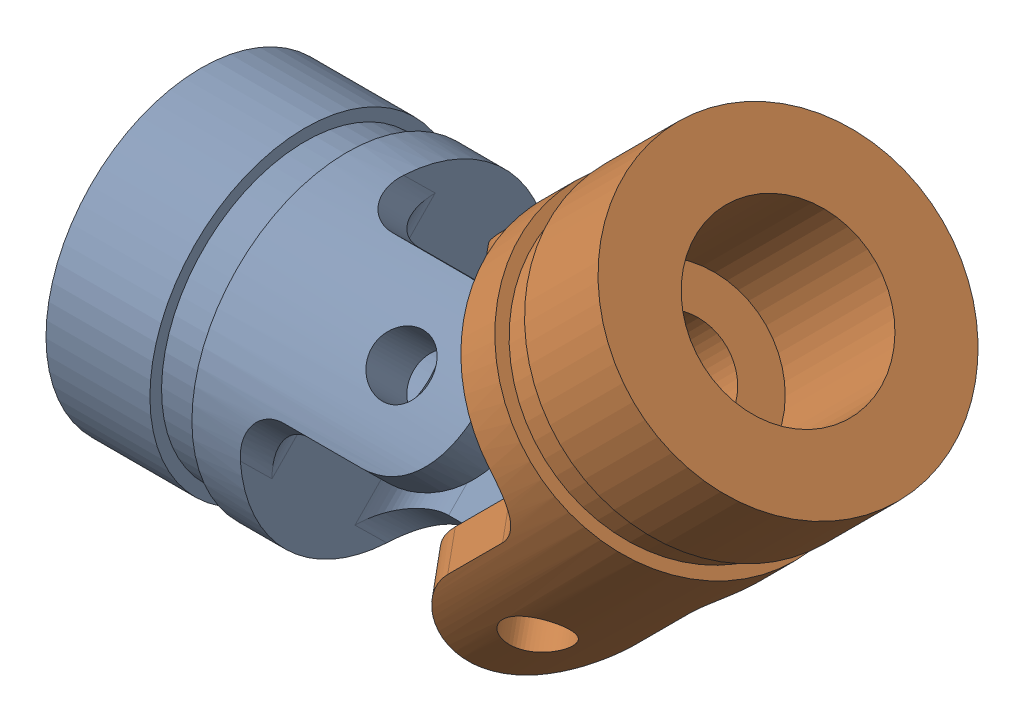
SolidWorks assembly UniversalJointAssembly, configuration Default. Lengths in mm.
Overall size (191.29 157.86 113.14).
2 component instances, 2 part files, 4 mates.
Components (placement in the parent):
- Part-1-1: Part-1 [Default] at (10 0 0) x (1 0 0) z (0 -0.713 0.701164) size (100 80 80)
- Part-2-1: Part-2 [Default] at (-9.4185 -9.4185 0) x (-0.707107 -0.707107 0) z (-0.498009 0.498009 0.709911) size (100 80 80)
Mates (geometry in assembly coordinates):
- Concentric3: concentric aligned: cylinder of Part-1-1 through (-50 0 0) axis (1 0 0) radius 12.5
- Universal Joint3: universal joint: cylinder of Part-1-1 through (-50 0 0) axis (1 0 0) radius 12.5; cylinder of Part-2-1 through (33.0079 33.0079 0) axis (-0.707107 -0.707107 0) radius 12.5
- Concentric4: concentric anti-aligned: cylinder of Part-2-1 through (61.2922 61.2922 0) axis (-0.707107 -0.707107 0) radius 22.5
- Distance1: distance = 90 mm: plane of assembly through (0 0 0) normal (1 0 0); plane of assembly; plane of Part-1-1 through (-90 28.0465 28.52) normal (-1 0 0)
